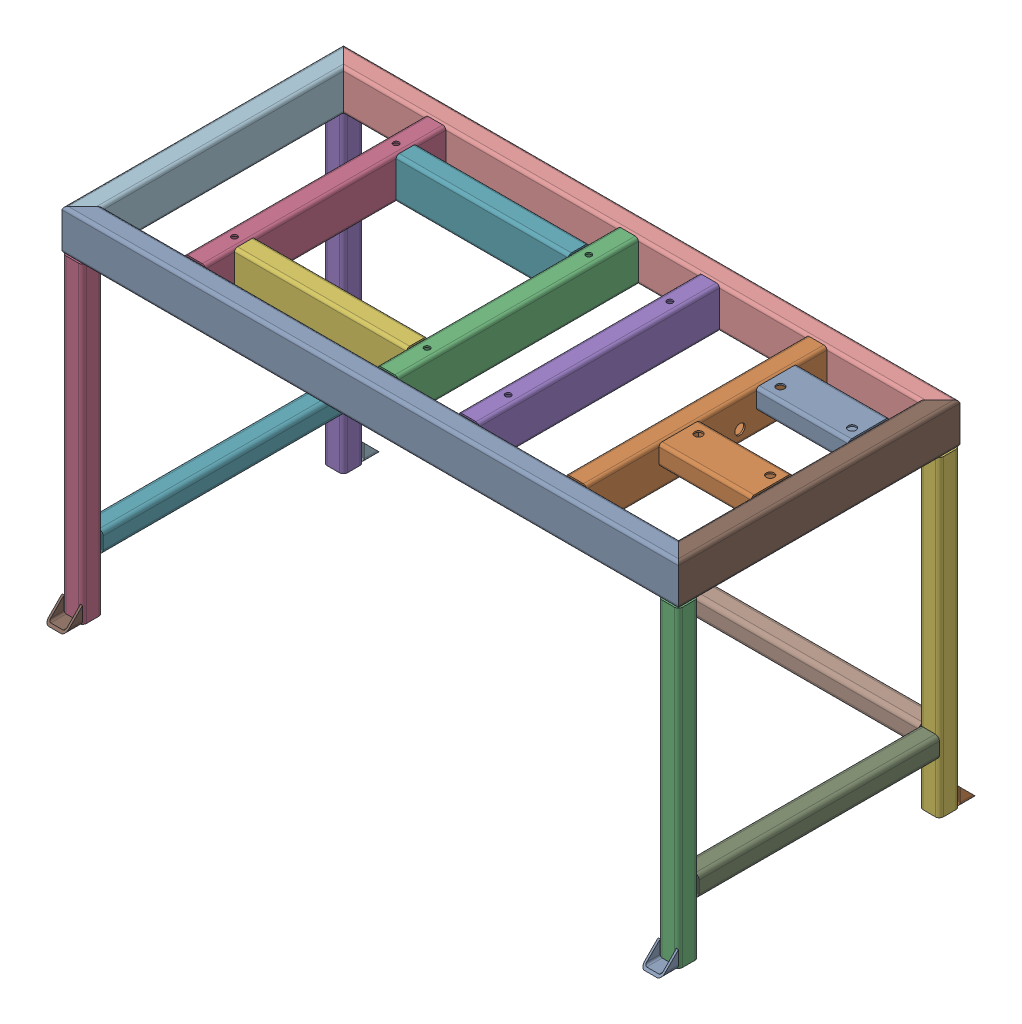
SolidWorks assembly SHRPRO-V1 1410.00-A Frame, configuration Predeterminado. Lengths in mm.
Overall size (1205 690 618.69).
8 component instances, 3 part files, 13 mates.
Components (placement in the parent):
- SHRPRO-V1 1410.01-A Frame-1: SHRPRO-V1 1410.01-A Frame [Défaut<Brut d'usinage>] at origin size (1205 690 550)
- SHRPRO-V1 1410.02-A L profile-1: SHRPRO-V1 1410.02-A L profile [Predeterminado] at (562.5 -329 235) x (1 0 0) z (0 1 0) size (30 30 30)
- SHRPRO-V1 1410.02-A L profile-2: SHRPRO-V1 1410.02-A L profile [Predeterminado] at (439.5 -40 235) x (0 1 0) z (-1 0 0) size (30 30 30)
- SHRPRO-V1 1410.02-A L profile-3: SHRPRO-V1 1410.02-A L profile [Predeterminado] at (562.5 -42 -31) x (0 -1 0) z (0 0 1) size (30 30 30)
- SHRPRO-V1 1410.03-A Squad-1: SHRPRO-V1 1410.03-A Squad [Predeterminado<Como mecanizada>] at (-582.5 -630 275) x (0 0 1) z (-1 0 0) size (34.34 34.34 40)
- SHRPRO-V1 1410.03-A Squad-2: SHRPRO-V1 1410.03-A Squad [Predeterminado<Como mecanizada>] at (-582.5 -630 -275) x (0 0 -1) z (1 0 0) size (34.34 34.34 40)
- SHRPRO-V1 1410.03-A Squad-3: SHRPRO-V1 1410.03-A Squad [Predeterminado<Como mecanizada>] at (582.5 -630 275) x (0 0 1) z (-1 0 0) size (34.34 34.34 40)
- SHRPRO-V1 1410.03-A Squad-4: SHRPRO-V1 1410.03-A Squad [Predeterminado<Como mecanizada>] at (582.5 -630 -275) x (0 0 -1) z (1 0 0) size (34.34 34.34 40)
Mates (geometry in assembly coordinates):
- Coincident10: coincident: plane of SHRPRO-V1 1410.01-A Frame-1 through (-570.5 -650 275) normal (0 0 1); plane of SHRPRO-V1 1410.03-A Squad-1 through (-570.5 -618 275) normal (0 0 -1)
- Coincident11: coincident: plane of SHRPRO-V1 1410.01-A Frame-1 through (-570.5 -650 267) normal (0 -1 0); plane of SHRPRO-V1 1410.03-A Squad-1 through (-594.5 -650 315) normal (0 -1 0)
- Coincident12: coincident: plane of SHRPRO-V1 1410.01-A Frame-1 through (-562.5 -650 267) normal (1 0 0); plane of SHRPRO-V1 1410.03-A Squad-1 through (-562.5 -618 315) normal (1 0 0)
- Coincident284: coincident: plane of SHRPRO-V1 1410.01-A Frame-1 through (582.5 -40 269) normal (0 -1 0); plane of SHRPRO-V1 1410.02-A L profile-2 through (409.5 -40 235) normal (0 1 0)
- Distance1: distance = 236 mm: plane of SHRPRO-V1 1410.02-A L profile-3 through (562.5 -42 -1) normal (0 0 1); plane of SHRPRO-V1 1410.01-A Frame-1 through (582.5 -34 235) normal (0 0 -1)
- Coordinate1: coordinate: point of SHRPRO-V1 1410.01-A Frame-1; point of assembly
- Distance3: distance = 2 mm: plane of SHRPRO-V1 1410.01-A Frame-1 through (596.5 -40 -255) normal (0 -1 0); plane of SHRPRO-V1 1410.02-A L profile-3 through (562.5 -42 -1) normal (0 -1 0)
- Coincident287: coincident: plane of SHRPRO-V1 1410.01-A Frame-1 through (562.5 -34 -255) normal (-1 0 0); plane of SHRPRO-V1 1410.02-A L profile-3 through (562.5 -42 -1) normal (1 0 0)
- Distance4: distance = 123 mm: plane of SHRPRO-V1 1410.02-A L profile-2 through (439.5 -40 235) normal (1 0 0); plane of SHRPRO-V1 1410.01-A Frame-1 through (562.5 -34 -255) normal (-1 0 0)
- Distance5: distance = 259 mm: plane of SHRPRO-V1 1410.01-A Frame-1 through (582.5 -40 269) normal (0 -1 0); plane of SHRPRO-V1 1410.02-A L profile-1 through (562.5 -299 235) normal (0 1 0)
- Distance6: coincident: plane of SHRPRO-V1 1410.01-A Frame-1 through (570.5 -650 235) normal (0 0 -1); plane of SHRPRO-V1 1410.02-A L profile-1 through (562.5 -299 235) normal (0 0 -1)
- Distance7: coincident: plane of SHRPRO-V1 1410.01-A Frame-1 through (582.5 -34 235) normal (0 0 -1); plane of SHRPRO-V1 1410.02-A L profile-2 through (409.5 -40 235) normal (0 0 -1)
- Coincident294: coincident: plane of SHRPRO-V1 1410.01-A Frame-1 through (562.5 -650 243) normal (-1 0 0); plane of SHRPRO-V1 1410.02-A L profile-1 through (562.5 -299 235) normal (1 0 0)
